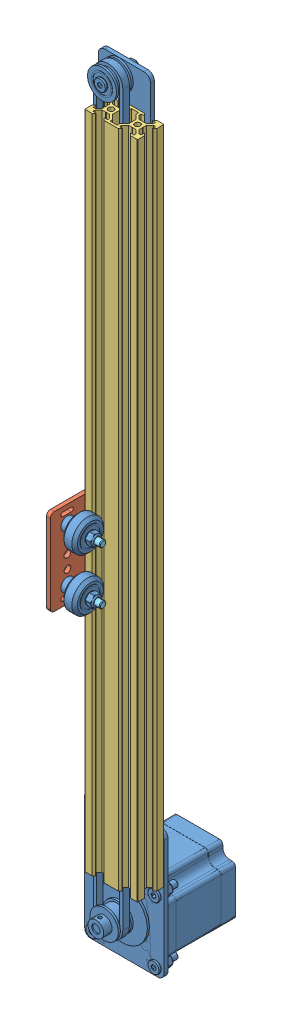
SolidWorks assembly Nema 23 V-Slot Belt Driven Actuator, configuration Default. Lengths in mm.
Overall size (60 592.65 98.62).
8 component instances, 5 part files, 0 mates.
Components (placement in the parent):
- Nema 23 V Slot Belt Driven Actuator 500mm-1: Nema 23 V Slot Belt Driven Actuator 500mm [Default] at origin size (60 592.65 97.67)
- V-Slot Gantry Plate 20mm-1: V-Slot Gantry Plate 20mm [Default] at (-16.3672 -288.5 19.8672) x (0 0 1) z (0 1 0) size (65.5 3 65.5)
- V-Slot 20x40x500 Linear Rail-1: V-Slot 20x40x500 Linear Rail [Default] at (10 0 20) x (0 0 1) z (0 -1 0) size (20 40 500)
- Aluminum Spacer 3mm-1: Aluminum Spacer 3mm [Default] at (0 20 10) size (10 10 3)
- Low Profile Screw M5 v1-1: Low Profile Screw M5 v1 [Default] at (4.1328 -267.71 0.0172) size (31.62 9 9)
- Low Profile Screw M5 v1-2: Low Profile Screw M5 v1 [Default] at (4.1328 -309.29 0.0172) size (31.62 9 9)
- Low Profile Screw M5 v1-3: Low Profile Screw M5 v1 [Default] at (3.6328 -268.5 39.7172) size (31.62 9 9)
- Low Profile Screw M5 v1-4: Low Profile Screw M5 v1 [Default] at (3.6328 -308.5 39.7172) size (31.62 9 9)
